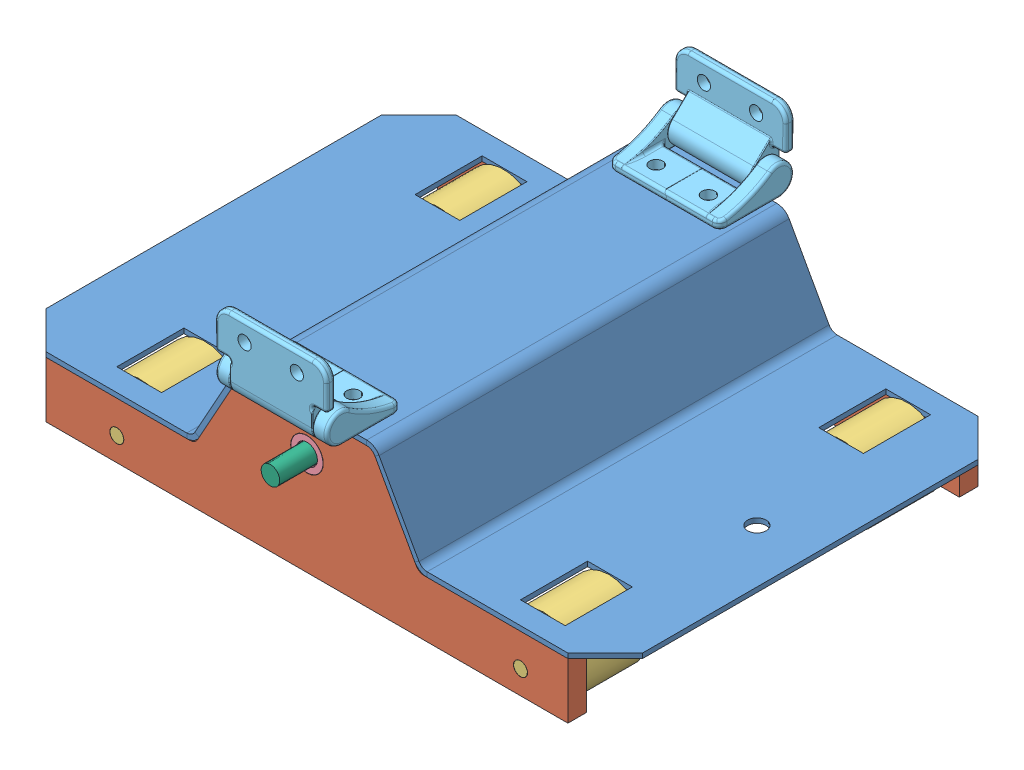
SolidWorks assembly DIAGNOSTIC, DYNO, TOP ASSY, configuration Default. Lengths in mm.
Overall size (203.2 81.68 159.25).
17 component instances, 6 part files, 17 mates.
Components (placement in the parent):
- DIAGNOSTIC, DYNO, CHASSIS, TOP ASSY-1: DIAGNOSTIC, DYNO, CHASSIS, TOP ASSY [Default] at (-124.166 -14.4263 81.7928) size (203.2 49.28 139.7)
  - DIAGNOSTIC, DYNO, TOP Cover-1: DIAGNOSTIC, DYNO, TOP Cover [Default] at (-3.5138 16.2458 -19.4505) size (203.2 30.23 139.7)
  - DIAGNOSTIC, DYNO, PLATE, Sidewall-1: DIAGNOSTIC, DYNO, PLATE, Sidewall [Default] at (-3.5138 16.2458 47.2245) size (177.8 47.62 6.35)
  - DIAGNOSTIC, DYNO, PLATE, Sidewall-2: DIAGNOSTIC, DYNO, PLATE, Sidewall [Default] at (-3.5138 16.2458 -86.1255) size (177.8 47.62 6.35)
- DIAGNOSTIC, DYNO, ROLLER-1: DIAGNOSTIC, DYNO, ROLLER [Default] at (-54.9341 -9.2295 113.1423) x (0.980458 0.196728 0) z (0 0 1) size (25.4 25.4 38.1)
- DIAGNOSTIC, DYNO, ROLLER-2: DIAGNOSTIC, DYNO, ROLLER [Default] at (-54.9341 -9.2295 11.5423) x (0.995823 0.091309 0) z (0 0 1) size (25.4 25.4 38.1)
- DIAGNOSTIC, DYNO, ROLLER-3: DIAGNOSTIC, DYNO, ROLLER [Default] at (-192.4497 -9.2295 113.1423) size (25.4 25.4 38.1)
- DIAGNOSTIC, DYNO, ROLLER-4: DIAGNOSTIC, DYNO, ROLLER [Default] at (-192.4497 -9.2295 11.5423) x (0.999619 0.027593 0) z (0 0 1) size (25.4 25.4 38.1)
- GYRO STATION, BEARING, MCMASTER 5905K210-1: GYRO STATION, BEARING, MCMASTER 5905K210 [5905K21] at (-127.6797 17.6945 -3.5389) size (11.11 11.11 7.94)
- GYRO STATION, BEARING, MCMASTER 5905K210-2: GYRO STATION, BEARING, MCMASTER 5905K210 [5905K21] at (-127.6797 17.6945 128.2236) size (11.11 11.11 7.94)
- DIAGNOSTIC, GYRO, MCMASTER HINGE-1: DIAGNOSTIC, GYRO, MCMASTER HINGE [Default] at (-144.2041 25.5974 -13.034) x (-1 0 0) z (0 1 0) size (38.06 25.62 25.5)
  - DIAGNOSTIC, GYRO, HINGE, MCMASTER 2190A210-1: DIAGNOSTIC, GYRO, HINGE, MCMASTER 2190A210 [Fixed] at (-22.0037 -21.9901 -16.7628) size (38.06 25.41 10.23)
  - DIAGNOSTIC, GYRO, HINGE, MCMASTER 2190A210-2: DIAGNOSTIC, GYRO, HINGE, MCMASTER 2190A210 [Moving] at (-22.0037 -24.8397 36.9806) x (1 0 0) z (0 0.999949 0.010128) size (38 25.4 10.21)
- DIAGNOSTIC, GYRO, MCMASTER HINGE-2: DIAGNOSTIC, GYRO, MCMASTER HINGE [Default] at (-112.0506 25.5974 141.7635) x (1 0 0) z (0 1 0) size (38.06 25.62 25.5)
  - DIAGNOSTIC, GYRO, HINGE, MCMASTER 2190A210-1: DIAGNOSTIC, GYRO, HINGE, MCMASTER 2190A210 [Fixed] at (-22.0037 -21.9901 -16.7628) size (38.06 25.41 10.23)
  - DIAGNOSTIC, GYRO, HINGE, MCMASTER 2190A210-2: DIAGNOSTIC, GYRO, HINGE, MCMASTER 2190A210 [Moving] at (-22.0037 -24.8397 36.9806) x (1 0 0) z (0 0.999949 0.010128) size (38 25.4 10.21)
- DIAGNOSTIC, RS-3705 MOTOR-1: DIAGNOSTIC, RS-3705 MOTOR [Default] at (-127.6797 17.6945 125.8423) x (1 0 0) z (0 1 0) size (25.4 83.31 25.4)
Mates (geometry in assembly coordinates):
- Concentric1: concentric aligned: cylinder of DIAGNOSTIC, DYNO, ROLLER-3 through (-192.4497 -9.2295 124.2548) axis (0 0 -1) radius 12.7; cylinder of DIAGNOSTIC, DYNO, ROLLER-4 through (-192.4497 -9.2295 22.6548) axis (0 0 -1) radius 12.7
- Concentric2: concentric aligned: cylinder of DIAGNOSTIC, DYNO, ROLLER-1 through (-54.9341 -9.2295 124.2548) axis (0 0 -1) radius 12.7; cylinder of DIAGNOSTIC, DYNO, ROLLER-2 through (-54.9341 -9.2295 22.6548) axis (0 0 -1) radius 12.7
- Coincident1: coincident aligned: plane of DIAGNOSTIC, DYNO, ROLLER-1 through (-54.9341 -9.2295 124.2548) normal (0 0 1); plane of DIAGNOSTIC, DYNO, ROLLER-3 through (-192.4497 -9.2295 124.2548) normal (0 0 1)
- Coincident2: coincident aligned: plane of DIAGNOSTIC, DYNO, ROLLER-2 through (-54.9341 -9.2295 0.4298) normal (0 0 -1); plane of DIAGNOSTIC, DYNO, ROLLER-4 through (-192.4497 -9.2295 0.4298) normal (0 0 -1)
- Concentric3: concentric anti-aligned: cylinder of DIAGNOSTIC, DYNO, CHASSIS, TOP ASSY-1/DIAGNOSTIC, DYNO, PLATE, Sidewall-2 through (-192.4497 -9.2295 -7.5077) axis (0 0 1) radius 2.3876; cylinder of DIAGNOSTIC, DYNO, ROLLER-3 through (-192.4497 -9.2295 132.1923) axis (0 0 -1) radius 2.3876
- Coincident3: coincident anti-aligned: circle of DIAGNOSTIC, DYNO, CHASSIS, TOP ASSY-1/DIAGNOSTIC, DYNO, PLATE, Sidewall-2; cylinder of DIAGNOSTIC, DYNO, ROLLER-2 through (-54.9341 -9.2295 30.5923) axis (0 0 -1) radius 2.3876
- Concentric4: concentric anti-aligned: cylinder of DIAGNOSTIC, DYNO, CHASSIS, TOP ASSY-1/DIAGNOSTIC, DYNO, PLATE, Sidewall-1 through (-127.6797 17.6945 132.1923) axis (0 0 -1) radius 5.5563; cylinder of GYRO STATION, BEARING, MCMASTER 5905K210-2 through (-127.6797 17.6945 132.1923) axis (0 0 1) radius 5.5563
- Coincident4: coincident aligned: plane of DIAGNOSTIC, DYNO, CHASSIS, TOP ASSY-1/DIAGNOSTIC, DYNO, PLATE, Sidewall-1 through (-87.7116 4.9945 132.1923) normal (0 0 1); plane of GYRO STATION, BEARING, MCMASTER 5905K210-2 through (-127.6797 23.2508 132.1923) normal (0 0 1)
- Coincident5: coincident aligned: plane of DIAGNOSTIC, DYNO, CHASSIS, TOP ASSY-1/DIAGNOSTIC, DYNO, PLATE, Sidewall-2 through (-87.7116 4.9945 -7.5077) normal (0 0 -1); plane of GYRO STATION, BEARING, MCMASTER 5905K210-1 through (-127.6797 21.2664 -7.5077) normal (0 0 -1)
- Concentric5: concentric anti-aligned: cylinder of DIAGNOSTIC, DYNO, CHASSIS, TOP ASSY-1/DIAGNOSTIC, DYNO, PLATE, Sidewall-2 through (-127.6797 17.6945 -1.1577) axis (0 0 -1) radius 5.5563; cylinder of GYRO STATION, BEARING, MCMASTER 5905K210-1 through (-127.6797 17.6945 0.4298) axis (0 0 1) radius 5.5563
- Symmetric1: symmetric aligned: plane of DIAGNOSTIC, DYNO, CHASSIS, TOP ASSY-1/DIAGNOSTIC, DYNO, TOP Cover-1 through (-127.6797 1.8195 62.3423) normal (0 0 1); plane of DIAGNOSTIC, DYNO, ROLLER-1 through (-54.9341 -9.2295 102.0298) normal (0 0 -1); plane of DIAGNOSTIC, DYNO, ROLLER-2 through (-54.9341 -9.2295 22.6548) normal (0 0 1)
- Distance1: distance = 1.5875 mm anti-aligned: plane of DIAGNOSTIC, DYNO, CHASSIS, TOP ASSY-1/DIAGNOSTIC, DYNO, PLATE, Sidewall-2 through (-87.7116 4.9945 -1.1577) normal (0 0 1); plane of DIAGNOSTIC, DYNO, ROLLER-2 through (-54.9341 -9.2295 0.4298) normal (0 0 -1)
- Coincident6: coincident anti-aligned: plane of DIAGNOSTIC, DYNO, CHASSIS, TOP ASSY-1/DIAGNOSTIC, DYNO, TOP Cover-1 through (-149.9047 32.0455 132.1923) normal (0 1 0); plane of DIAGNOSTIC, GYRO, MCMASTER HINGE-2/DIAGNOSTIC, GYRO, HINGE, MCMASTER 2190A210-1 through (-129.9472 32.0455 117.7336) normal (0 -1 0)
- Coincident7: coincident anti-aligned: plane of DIAGNOSTIC, DYNO, CHASSIS, TOP ASSY-1/DIAGNOSTIC, DYNO, TOP Cover-1 through (-149.9047 32.0455 132.1923) normal (0 1 0); plane of DIAGNOSTIC, GYRO, MCMASTER HINGE-1/DIAGNOSTIC, GYRO, HINGE, MCMASTER 2190A210-1 through (-128.3074 32.0455 10.9959) normal (0 -1 0)
- Coincident9: coincident anti-aligned: plane of DIAGNOSTIC, DYNO, CHASSIS, TOP ASSY-1/DIAGNOSTIC, DYNO, TOP Cover-1 through (-149.9047 30.3945 132.1923) normal (0 -1 0); plane of DIAGNOSTIC, RS-3705 MOTOR-1 through (-140.3797 30.3945 119.7463) normal (0 1 0)
- Coincident10: coincident anti-aligned: plane of DIAGNOSTIC, DYNO, CHASSIS, TOP ASSY-1/DIAGNOSTIC, DYNO, PLATE, Sidewall-1 through (-87.7116 4.9945 125.8423) normal (0 0 -1); plane of DIAGNOSTIC, RS-3705 MOTOR-1 through (-140.3797 30.3945 125.8423) normal (0 0 1)
- Concentric6: concentric anti-aligned: cylinder of GYRO STATION, BEARING, MCMASTER 5905K210-2 through (-127.6797 17.6945 132.1923) axis (0 0 1) radius 4.7625; cylinder of DIAGNOSTIC, RS-3705 MOTOR-1 through (-127.6797 17.6945 144.6383) axis (0 0 -1) radius 3.175
